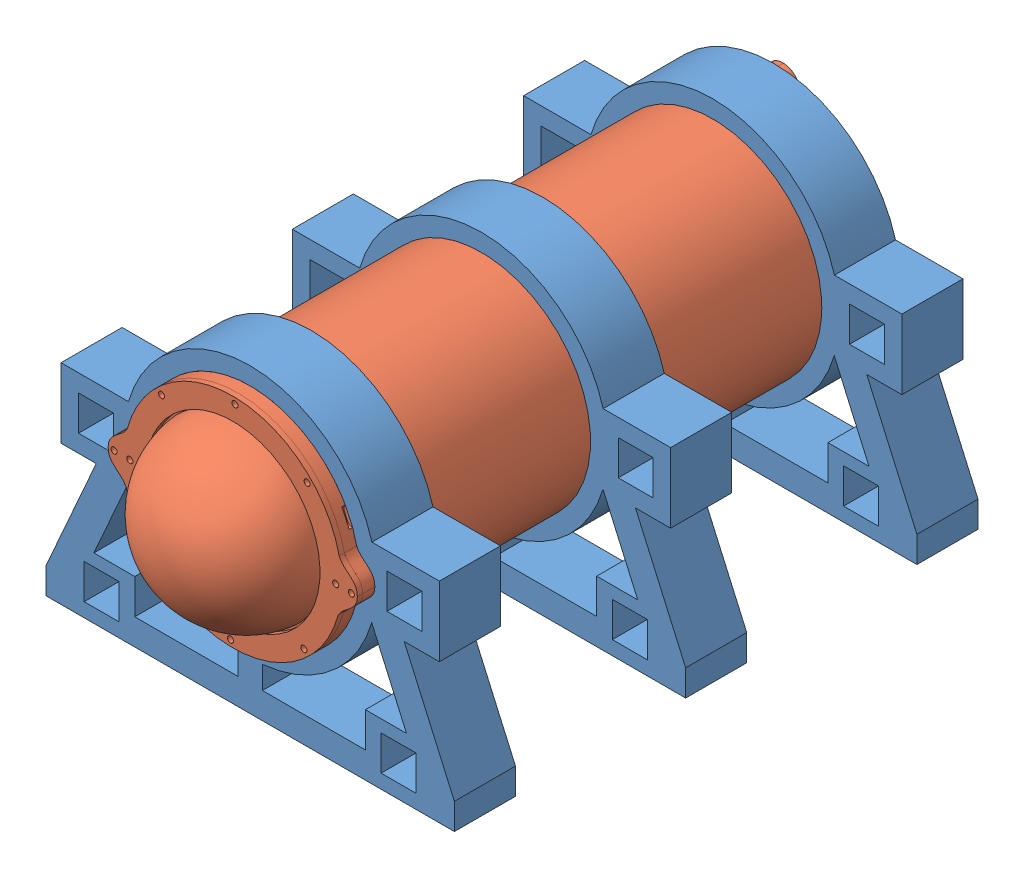
SolidWorks assembly tup30cmbirlesik, configuration Varsayılan. Lengths in mm.
Overall size (234 173.21 358.25).
4 component instances, 2 part files, 8 mates.
Components (placement in the parent):
- auv_on-1: auv_on [Varsayılan] at (-0.4985 6.4776 216.5) size (234 172.66 35)
- auvtup30cm-1: auvtup30cm [Default] at (13.0956 8.6338 230.5) x (0.999767 -0.021578 0) z (0 0 1) size (143.05 134.03 358.25)
- auv_on-2: auv_on [Varsayılan] at (-0.4985 6.4776 349) size (234 172.66 35)
- auv_on-3: auv_on [Varsayılan] at (-0.4985 6.4776 481.5) size (234 172.66 35)
Mates (geometry in assembly coordinates):
- Concentric1: concentric: cylinder of auvtup30cm-1 through (-0.4985 6.4776 516.5) axis (0 0 -1) radius 62.5; cylinder of auv_on-3 through (-0.4985 6.4776 516.5) axis (0 0 -1) radius 62.5
- Concentric2: concentric: cylinder of auv_on-1 through (-0.4985 6.4776 251.5) axis (0 0 -1) radius 62.5; cylinder of auvtup30cm-1 through (-0.4985 6.4776 516.5) axis (0 0 -1) radius 62.5
- Concentric3: concentric: cylinder of auvtup30cm-1 through (-0.4985 6.4776 516.5) axis (0 0 -1) radius 62.5; cylinder of auv_on-2 through (-0.4985 6.4776 384) axis (0 0 -1) radius 62.5
- Coincident1: coincident: circle of auv_on-1; circle of auvtup30cm-1
- Coincident2: coincident: circle of auvtup30cm-1; circle of auv_on-3
- Width1: width: plane of auv_on-2 through (-0.4985 6.4776 384) normal (0 0 1); plane of auv_on-3 through (-0.4985 6.4776 349) normal (0 0 -1); plane of auv_on-2 through (-0.4985 6.4776 481.5) normal (0 0 -1); plane of auv_on-1 through (-0.4985 6.4776 251.5) normal (0 0 1)
- Parallel1: parallel: line of auv_on-1 through (77.8803 16.2959 251.5) axis (1 0 0); line of auv_on-2 through (77.8803 16.2959 384) axis (1 0 0)
- Parallel2: parallel: line of auv_on-2 through (77.8803 16.2959 384) axis (1 0 0); line of auv_on-3 through (77.8803 16.2959 481.5) axis (1 0 0)
